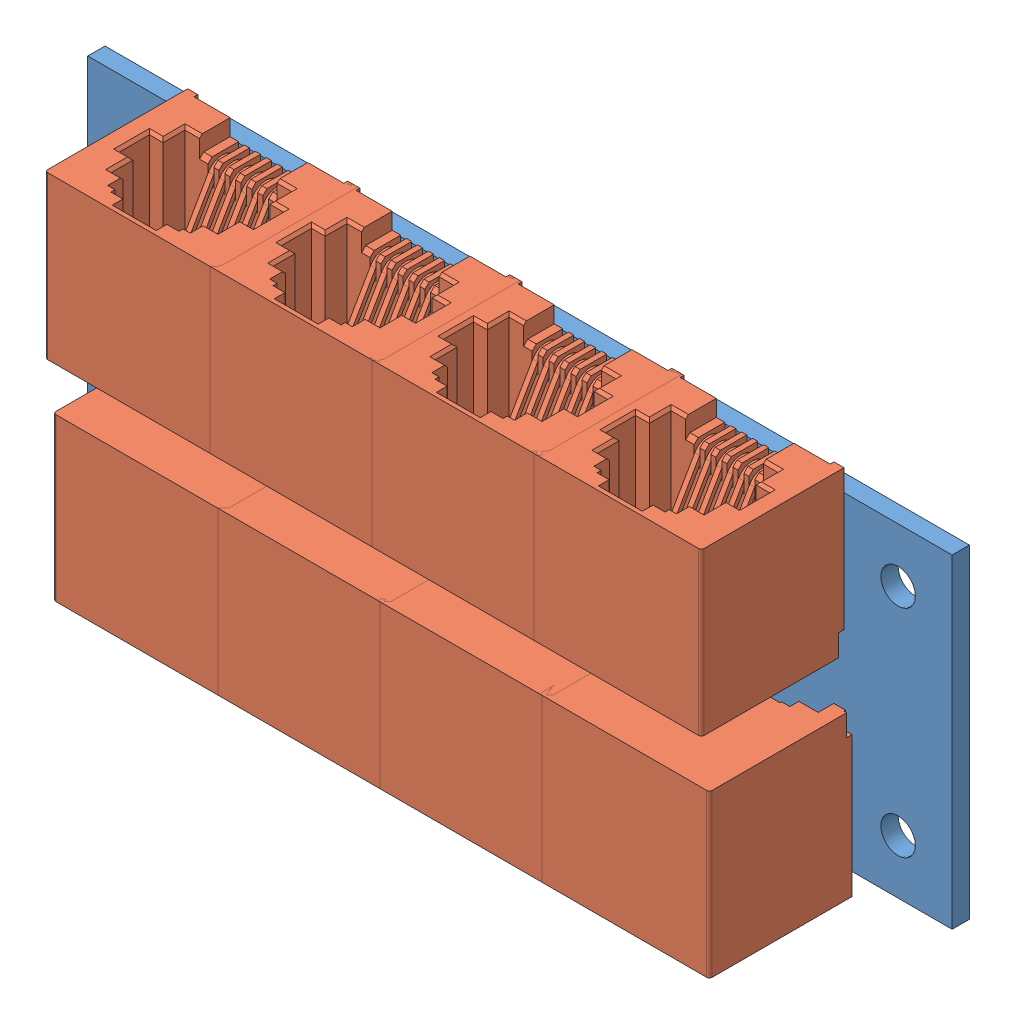
SolidWorks assembly ICD3Board, configuration Default. Lengths in mm.
Overall size (80 34 16.36).
9 component instances, 2 part files, 3 mates.
Components (placement in the parent):
- ICD3BoardSupport-1: ICD3BoardSupport [Default] at (29.1948 40.7842 61.6139) size (80 30 1.6)
- User Library-RJ11-6PM-1: User Library-RJ11-6PM [Default] at (7.0688 31.2772 69.8179) x (1 0 0) z (0 -1 0) size (15.88 16.36 14.99)
- User Library-RJ11-6PM-2: User Library-RJ11-6PM [Default] at (22.0688 31.2772 69.8179) x (1 0 0) z (0 -1 0) size (15.88 16.36 14.99)
- User Library-RJ11-6PM-3: User Library-RJ11-6PM [Default] at (37.0688 31.2772 69.8179) x (1 0 0) z (0 -1 0) size (15.88 16.36 14.99)
- User Library-RJ11-6PM-4: User Library-RJ11-6PM [Default] at (52.0688 31.2772 69.8179) x (1 0 0) z (0 -1 0) size (15.88 16.36 14.99)
- User Library-RJ11-6PM-10: User Library-RJ11-6PM [Default] at (51.3208 50.2912 69.8179) x (-1 0 0) z (0 1 0) size (15.88 16.36 14.99)
- User Library-RJ11-6PM-11: User Library-RJ11-6PM [Default] at (36.3208 50.2912 69.8179) x (-1 0 0) z (0 1 0) size (15.88 16.36 14.99)
- User Library-RJ11-6PM-12: User Library-RJ11-6PM [Default] at (21.3208 50.2912 69.8179) x (-1 0 0) z (0 1 0) size (15.88 16.36 14.99)
- User Library-RJ11-6PM-13: User Library-RJ11-6PM [Default] at (6.3208 50.2912 69.8179) x (-1 0 0) z (0 1 0) size (15.88 16.36 14.99)
Mates (geometry in assembly coordinates):
- Coïncidente1: coincident anti-aligned: plane of ICD3BoardSupport-1 through (29.1948 40.7842 63.2139) normal (0 0 1); plane of User Library-RJ11-6PM-1 through (-0.8052 38.7702 63.2139) normal (0 0 -1)
- Distance1: distance = 2 mm aligned: plane of ICD3BoardSupport-1 through (-10.8052 25.7842 63.2139) normal (0 -1 0); plane of User Library-RJ11-6PM-1 through (7.0688 23.7842 69.8179) normal (0 -1 0)
- Distance2: distance = 10 mm aligned: plane of User Library-RJ11-6PM-1 through (-0.8052 38.7702 76.4219) normal (-1 0 0); plane of ICD3BoardSupport-1 through (-10.8052 55.7842 63.2139) normal (-1 0 0)
